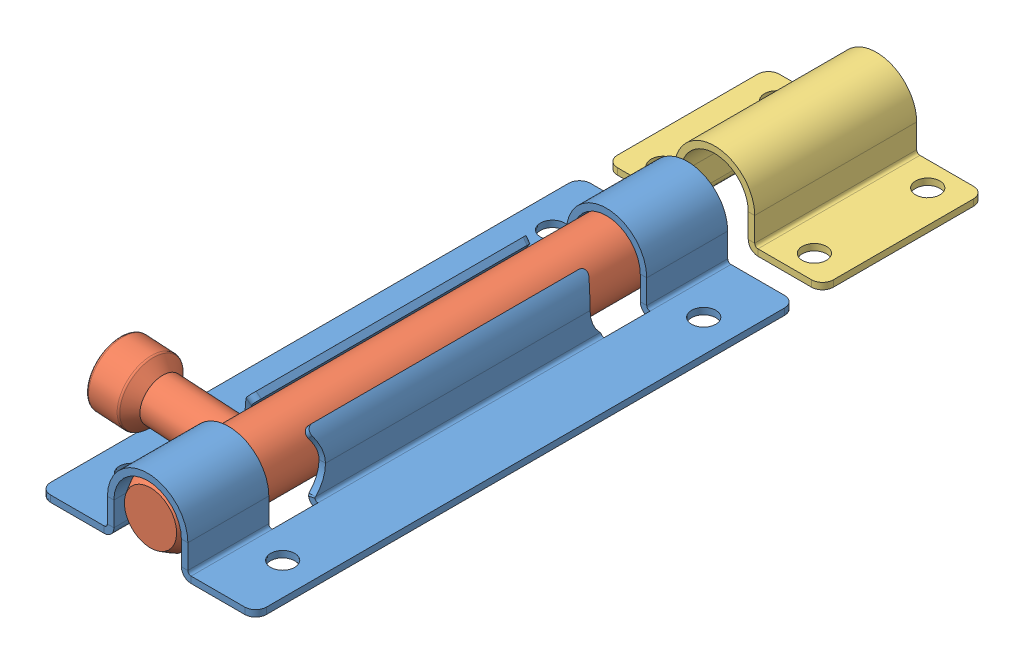
SolidWorks assembly zapah, configuration Default. Lengths in mm.
Overall size (45.32 13.87 135).
3 component instances, 3 part files, 6 mates.
Components (placement in the parent):
- zapah 3-1: zapah 3 [Default] at origin size (40 13.7 100)
- zapah 1-1: zapah 1 [Default] at (0 6.25 0.4736) x (0.061049 0.998135 0) z (0 0 1) size (12 31 98)
- zapah 2-1: zapah 2 [Default] at (0 0 -70) size (40 13.7 30)
Mates (geometry in assembly coordinates):
- Concentric3: concentric aligned: cylinder of zapah 3-1 through (0 6.25 102.2964) axis (0 0 -1) radius 6.25; cylinder of zapah 1-1 through (0 6.25 49.4736) axis (0 0 -1) radius 6
- LimitDistance1: limit distance = -0.4736 mm aligned: plane of zapah 3-1 through (0 0 0) normal (0 0 1); plane of zapah 1-1 through (0 6.25 0.4736) normal (0 0 1)
- LimitAngle2: limit planar angle = 0.061087 rad aligned: plane of zapah 1-1 through (0 6.25 0.4736) normal (0.061049 0.998135 0); plane of zapah 3-1 through (0 0 0) normal (0 1 0)
- Concentric4: concentric anti-aligned: cylinder of zapah 3-1 through (0 6.25 102.2964) axis (0 0 -1) radius 6.25; cylinder of zapah 2-1 through (0 6.25 -85) axis (0 0 1) radius 6.25
- Coincident3: coincident aligned: plane of zapah 3-1 through (20 0 -50) normal (0 -1 0); plane of zapah 2-1 through (20 0 -85) normal (0 -1 0)
- Distance2: distance = 5 mm anti-aligned: plane of zapah 2-1 through (-7.45 6.25 -55) normal (0 0 1); plane of zapah 3-1 through (-7.45 6.25 -50) normal (0 0 -1)
